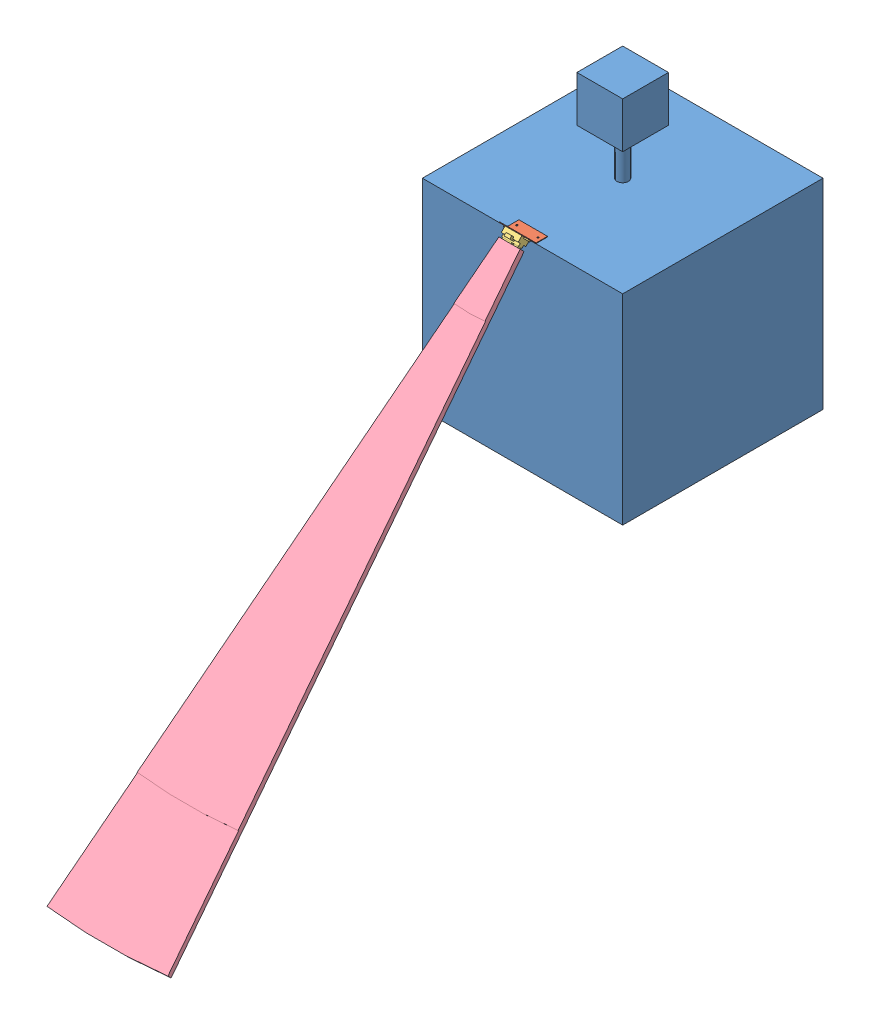
SolidWorks assembly robot_adverse_bleu_capteur, configuration Défaut. Lengths in mm.
Overall size (350 874.87 1078.47).
5 component instances, 4 part files, 2 mates.
Components (placement in the parent):
- robot_adverse_bleu-1: robot_adverse_bleu [Défaut] at (-306.7262 -209.8783 175) size (350 510 350)
- capteur_front_champ_45deg-1: capteur_front_champ_45deg [Default] at (-132.988 161.1562 172.0149) x (0 1 0) z (0 0 1) size (732.46 211.17 748.89)
  - corniere_angle45_H50_l20-1: corniere_angle45_H50_l20 [Default] at (-21.0346 -24.5362 2.9851) size (15.14 50 34.85)
  - GP2D12-1: GP2D12 [Default] at (-6.9885 -14.2862 17.0313) x (0 1 0) z (0.707107 0 0.707107) size (44.5 15.6 23.9)
  - champ_GP2D12-1: champ_GP2D12 [Défaut] at (-28.8027 0.2138 17.2787) x (0 1 0) z (0.707107 0 -0.707107) size (211.17 10 1000)
Mates (geometry in assembly coordinates):
- Coïncidente1: coincident: plane of robot_adverse_bleu-1 through (-306.7262 140.1217 -175) normal (0 1 0); plane of capteur_front_champ_45deg-1/corniere_angle45_H50_l20-1 through (-158.4518 140.1217 175) normal (0 -1 0)
- Coïncidente2: coincident aligned: line of robot_adverse_bleu-1; line of capteur_front_champ_45deg-1/corniere_angle45_H50_l20-1
